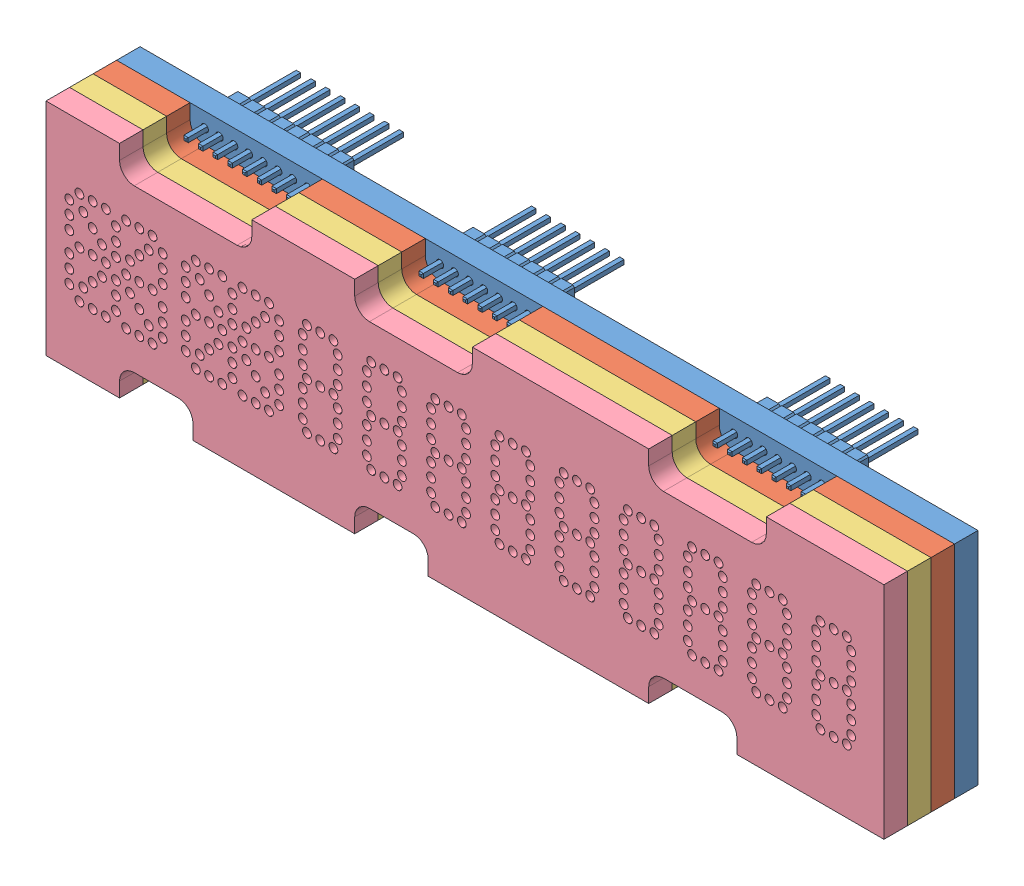
SolidWorks assembly ufc_v4_scratchpad_disp, configuration Default. Lengths in mm.
Overall size (57 15 11.25).
4 component instances, 4 part files, 10 mates.
Components (placement in the parent):
- ufc_v4_scratchpad-1: ufc_v4_scratchpad [Default] at origin size (57 15 7.8)
- ufc_v4_scratchpad_layer2-1: ufc_v4_scratchpad_layer2 [Default] at (0 0 1.6) size (57 15 1.6)
- ufc_v4_scratchpad_layer3-1: ufc_v4_scratchpad_layer3 [Default] at (0 0 3.2) size (57 15 1.6)
- ufc_v4_scratchpad_layer4-1: ufc_v4_scratchpad_layer4 [Default] at (0 0 4.8) size (57 15 1.6)
Mates (geometry in assembly coordinates):
- Coincident1: coordinate: point of ufc_v4_scratchpad-1
- Coincident2: coincident anti-aligned: plane of ufc_v4_scratchpad-1 through (0 0 1.6) normal (0 0 1); plane of ufc_v4_scratchpad_layer2-1 through (-0.3151 -0.1107 1.6) normal (0 0 -1)
- Coincident7: coincident aligned: plane of ufc_v4_scratchpad-1 through (28.5 7.5 0) normal (0 1 0); plane of ufc_v4_scratchpad_layer3-1 through (20.5 7.5 20.6573) normal (0 1 0)
- Coincident8: coincident aligned: plane of ufc_v4_scratchpad-1 through (28.5 7.5 0) normal (0 1 0); plane of ufc_v4_scratchpad_layer4-1 through (20.5 7.5 22.2573) normal (0 1 0)
- Coincident9: coincident aligned: plane of ufc_v4_scratchpad-1 through (28.5 7.5 0) normal (0 1 0); plane of ufc_v4_scratchpad_layer2-1 through (28.5 7.5 1.6) normal (0 1 0)
- Coincident10: coincident aligned: plane of ufc_v4_scratchpad-1 through (28.5 -7.5 0) normal (1 0 0); plane of ufc_v4_scratchpad_layer3-1 through (28.5 7.5 20.6573) normal (1 0 0)
- Coincident11: coincident aligned: plane of ufc_v4_scratchpad-1 through (28.5 -7.5 0) normal (1 0 0); plane of ufc_v4_scratchpad_layer4-1 through (28.5 7.5 22.2573) normal (1 0 0)
- Coincident12: coincident aligned: plane of ufc_v4_scratchpad-1 through (28.5 -7.5 0) normal (1 0 0); plane of ufc_v4_scratchpad_layer2-1 through (28.5 -7.5 1.6) normal (1 0 0)
- Coincident13: coincident anti-aligned: plane of ufc_v4_scratchpad_layer3-1 through (-0.3151 -0.1107 22.2573) normal (0 0 1); plane of ufc_v4_scratchpad_layer4-1 through (-0.3151 -0.1107 22.2573) normal (0 0 -1)
- Coincident14: coincident anti-aligned: plane of ufc_v4_scratchpad_layer2-1 through (-0.3151 -0.1107 3.2) normal (0 0 1); plane of ufc_v4_scratchpad_layer3-1 through (-0.3151 -0.1107 3.2) normal (0 0 -1)
